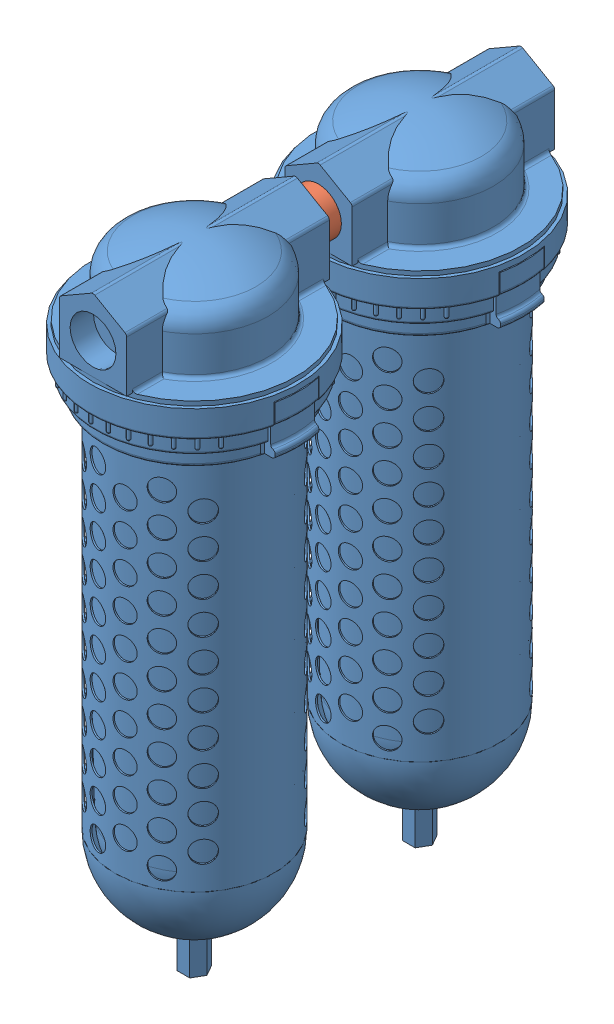
SolidWorks assembly ReadingTech_4P-090-P06-DC, configuration Default. Lengths in mm.
Overall size (121.86 369.43 252.73).
3 component instances, 2 part files, 3 mates.
Components (placement in the parent):
- ReadingTech_3P090P06F-1: ReadingTech_3P090P06F [Default] at (-50.538 -210.8282 14.7634) size (121.86 369.43 121.67)
- ReadingTech_3P090P06F-2: ReadingTech_3P090P06F [Default] at (-50.538 -210.8282 -116.3006) size (121.86 369.43 121.67)
- ReadingTech- 90,150cfm_connector_.75in-1: ReadingTech- 90,150cfm_connector_.75in [Default] at (-50.538 178.1728 -44.1646) x (1 0 0) z (0 1 0) size (26.67 13.21 26.67)
Mates (geometry in assembly coordinates):
- Coincident1: coincident anti-aligned: circle of ReadingTech_3P090P06F-2; circle of ReadingTech- 90,150cfm_connector_.75in-1
- Coincident2: coincident aligned: circle of ReadingTech_3P090P06F-1; circle of ReadingTech- 90,150cfm_connector_.75in-1
- Coincident3: coincident aligned: plane of ReadingTech_3P090P06F-1 through (-30.98 190.8728 73.6914) normal (1 0 0); plane of ReadingTech_3P090P06F-2 through (-30.98 190.8728 -57.3726) normal (1 0 0)
